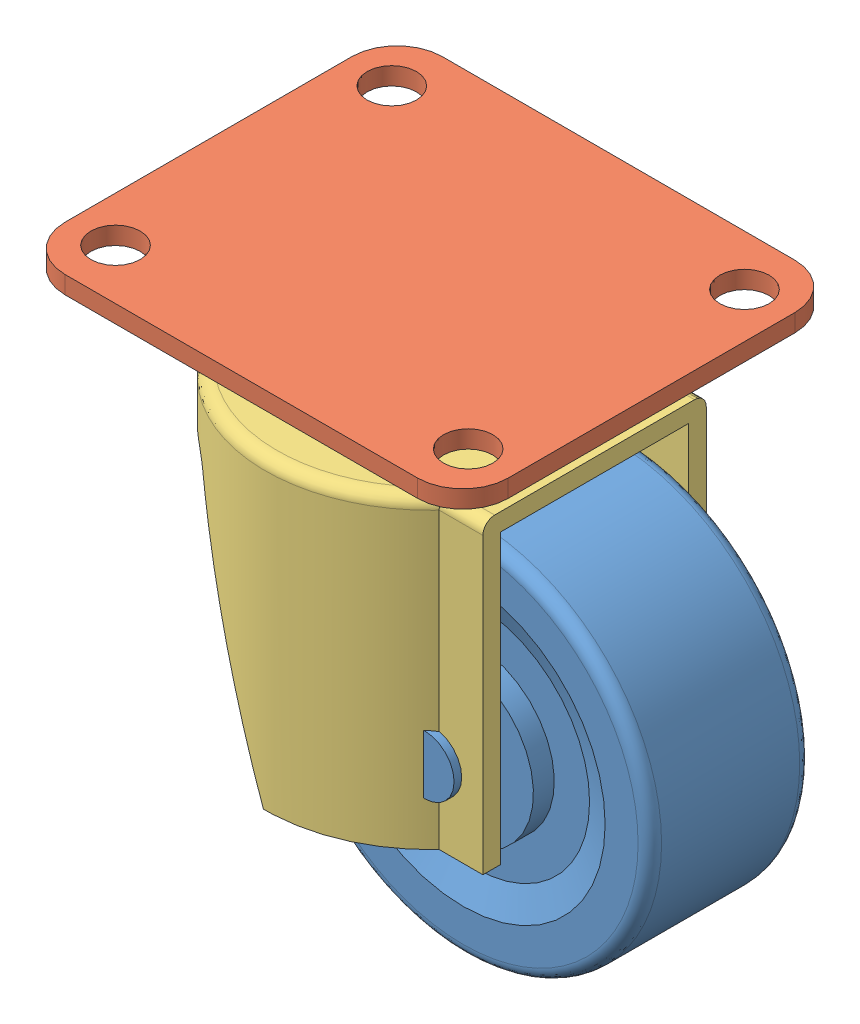
SolidWorks assembly Caster, configuration Default. Lengths in mm.
Overall size (44.42 42.6 32.1).
3 component instances, 3 part files, 6 mates.
Components (placement in the parent):
- Caster Wheel-3: Caster Wheel [Default] at (32.504 19.8447 -30.6341) x (0 1 0) z (0 0 1) size (31.75 31.75 20.3)
- Caster Base-1: Caster Base [Default] at (22.804 45.0697 -30.6341) x (-1 0 0) z (0 0 -1) size (37.7 4 32.1)
- Caster Body-1: Caster Body [Default] at (22.804 13.5697 -30.6341) x (-1 0 0) z (0 0 -1) size (28 26 28)
Mates (geometry in assembly coordinates):
- Coincident2: coincident anti-aligned: plane of Caster Wheel-3 through (32.504 46.5697 -30.6341) normal (0 -1 0); plane of Caster Base-1 through (22.804 46.5697 -30.6341) normal (0 1 0)
- Distance1: distance = 3 mm anti-aligned: plane of Caster Body-1 through (22.804 39.5697 -30.6341) normal (0 1 0); plane of Caster Base-1 through (22.804 42.5697 -30.6341) normal (0 -1 0)
- Concentric1: concentric anti-aligned: circle of Caster Base-1; circle of Caster Body-1
- Coincident5: coincident aligned: line of Caster Wheel-3 through (22.804 37.3072 -30.6341) axis (0 -1 0); line of Caster Base-1 through (22.804 45.0697 -30.6341) axis (0 -1 0)
- Parallel1: parallel anti-aligned: plane of Caster Wheel-3 through (32.504 22.3447 -40.7841) normal (0 0 -1); plane of Caster Body-1 through (22.804 13.5697 -38.6341) normal (0 0 1)
- Angle1: planar angle = 0 rad anti-aligned: plane of Caster Base-1 through (41.654 46.5697 -46.6841) normal (0 0 -1); plane of Caster Wheel-3 through (32.504 19.8447 -30.6341) normal (0 0 1)
